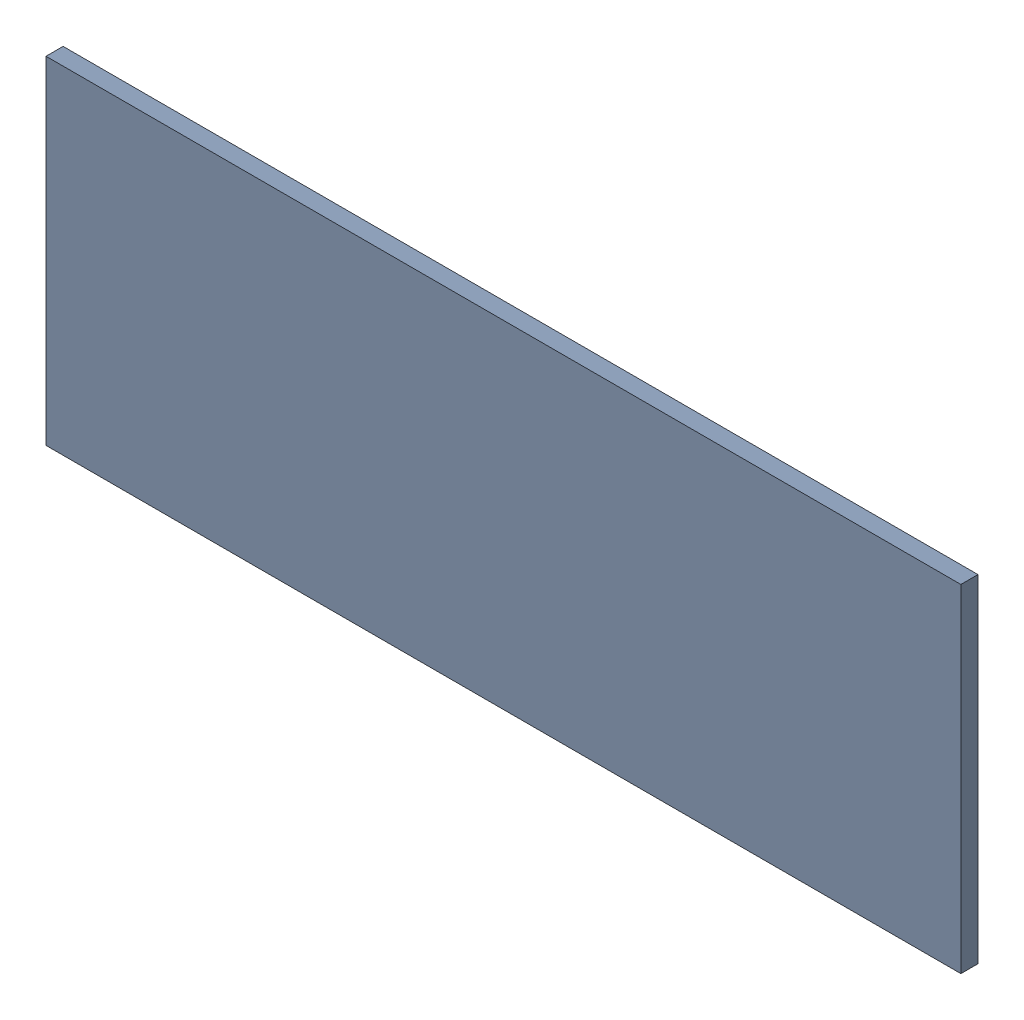
SolidWorks assembly Pad RAK4600-22(29.2mm,12.5mm) on Top Layer, configuration Predeterminado. Lengths in mm.
Overall size (1.9 0.7 0.04).
2 component instances, 1 part files, 0 mates.
Components (placement in the parent):
- Pad RAK4600-22(29.2mm,12.5mm) on Top Layer-1-1: Pad RAK4600-22(29.2mm,12.5mm) on Top Layer-1 [Predeterminado] at (-68.317 -44.187 -0.0457) size (1.9 0.7 0.04)
  - Pad RAK4600-22(29.2mm,12.5mm) on Top Layer-Part-1-1: Pad RAK4600-22(29.2mm,12.5mm) on Top Layer-Part-1 [Predeterminado] at origin size (1.9 0.7 0.04)
